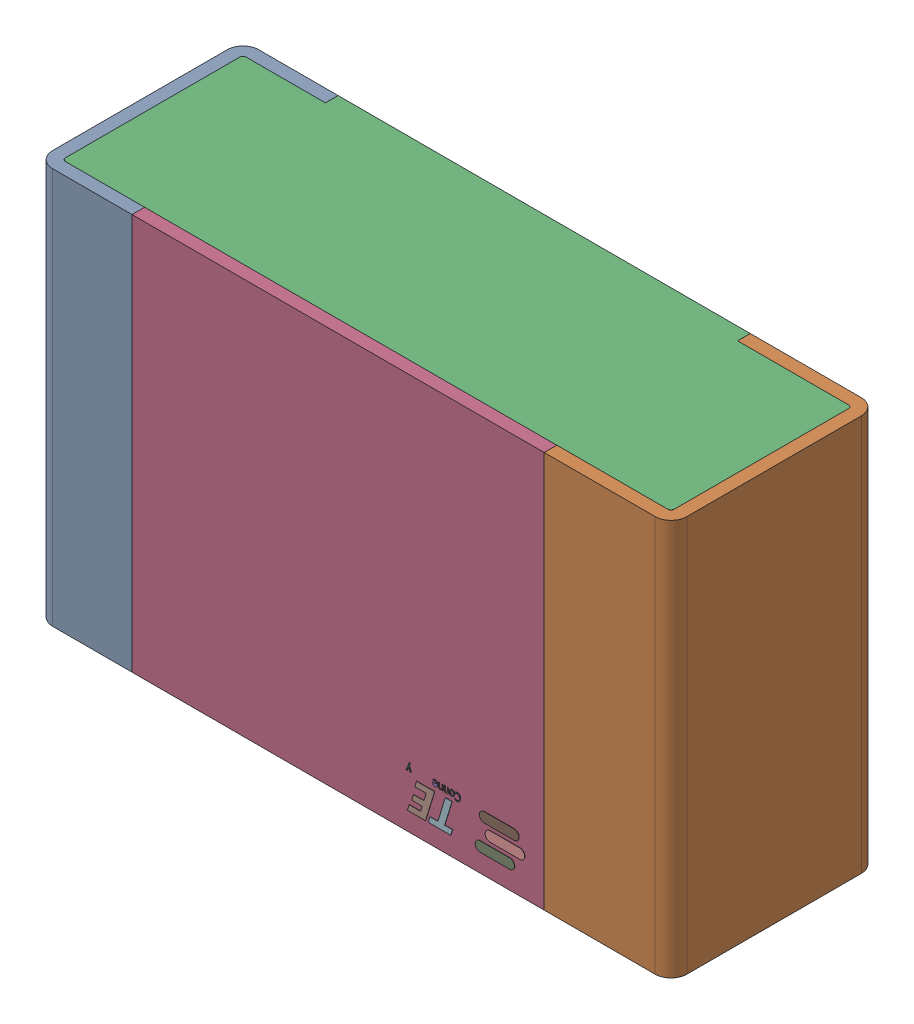
SolidWorks assembly RLL3.step, configuration Default. Lengths in mm.
Overall size (2 1.25 0.65).
5 component instances, 4 part files, 0 mates.
Components (placement in the parent):
- Res_TE_Connectivity_CPF0805B66R5E1_eec.step-1: Res_TE_Connectivity_CPF0805B66R5E1_eec.step [Default] at (10.287 17.272 0) x (-1 0 0) z (0 0 1) size (2 1.25 0.65)
  - 1.step-1: 1.step [Default] at origin size (2 1.25 0.65)
  - 2.step-1: 2.step [Default] at origin size (1.92 1.25 0.61)
  - 3.step-1: 3.step [Default] at origin size (1.3 1.25 0.04)
  - TE connectivity Logo 1 (2).step-1: TE connectivity Logo 1 (2).step [Default] at (5.4285 0.313 0.551) x (-1 0 0) z (0 0 1) size (0.37 0.13 0.11)
